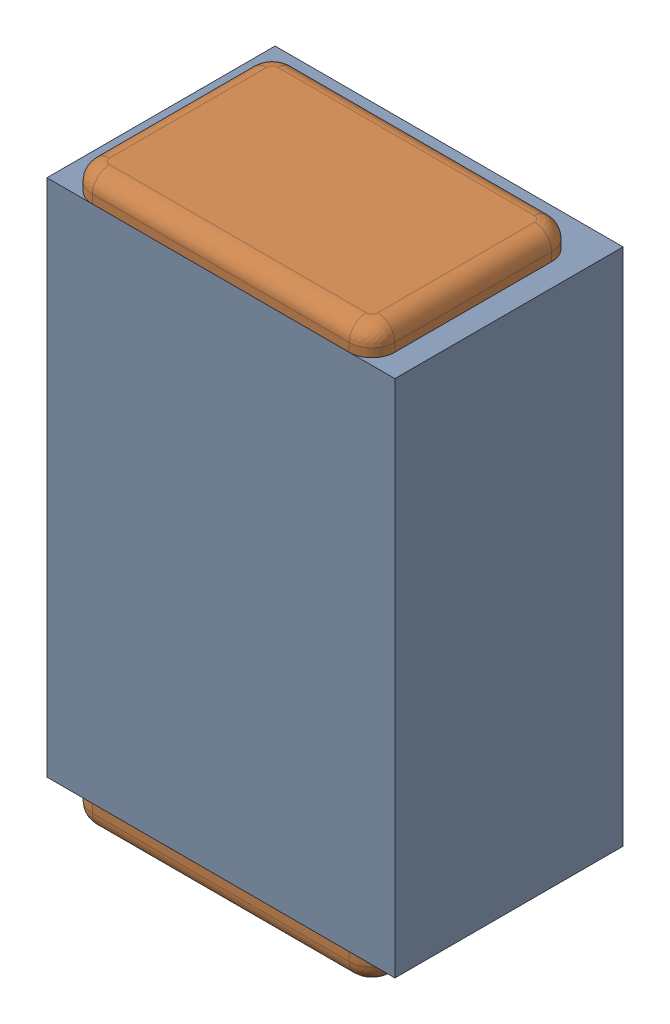
SolidWorks assembly C27, configuration Default. Lengths in mm.
Overall size (0.61 1 0.4).
3 component instances, 2 part files, 0 mates.
Components (placement in the parent):
- 1088881848-1: 1088881848 [Default] at (15 38.6 -2.044) size (0.61 0.91 0.4)
  - Extruded-1-1: Extruded-1 [Default] at origin size (0.61 0.91 0.4)
- C0402-1: C0402 [Default] at (14.9999 38.5999 -1.644) x (0 -1 0) z (1 0 0) size (1 0.36 0.54)
